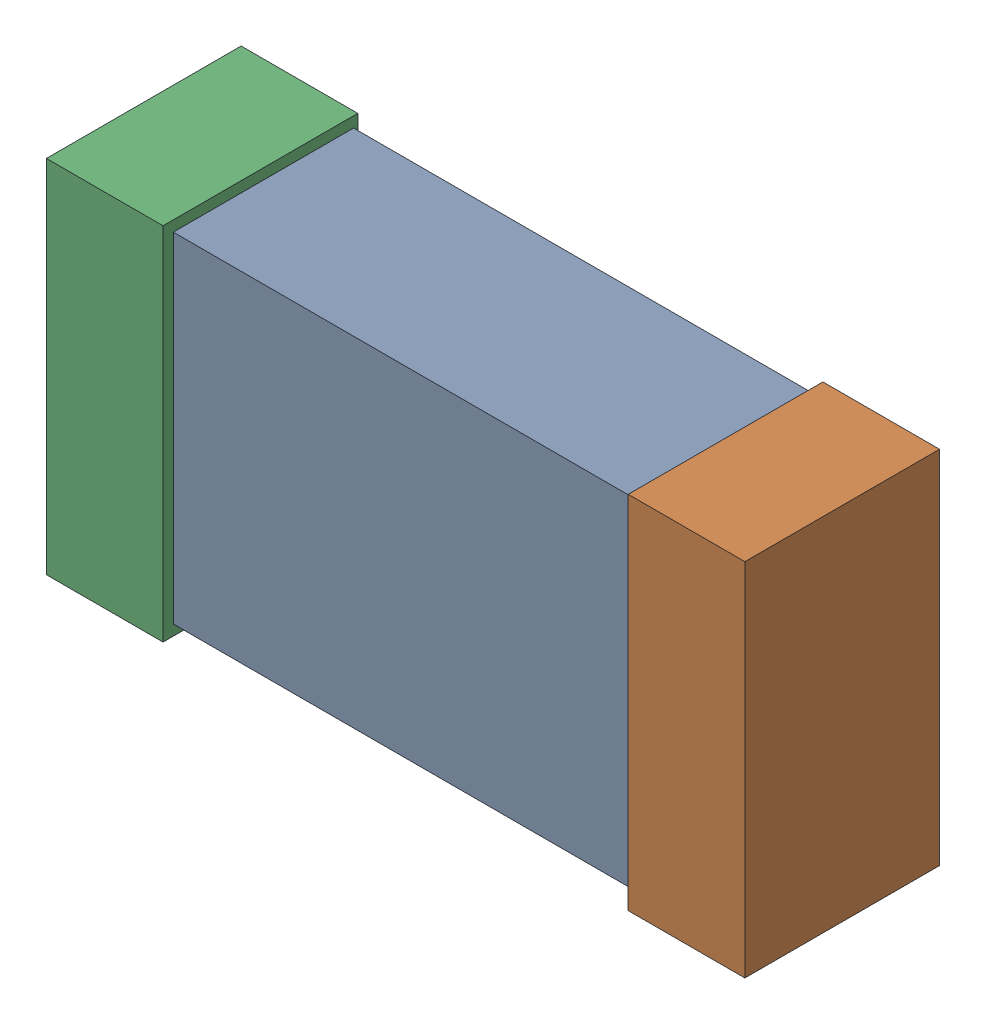
SolidWorks assembly R2, configuration Default. Lengths in mm.
Overall size (1.65 0.85 0.46).
6 component instances, 2 part files, 0 mates.
Components (placement in the parent):
- 432120720_14-1: 432120720_14 [Default] at (48.1003 12.0634 -0.8615) size (1.5 0.8 0.42)
  - Extruded (12)-1: Extruded (12) [Default] at origin size (1.5 0.8 0.42)
- 432120464_30-1: 432120464_30 [Default] at (48.7861 12.0634 -0.8715) size (0.28 0.85 0.46)
  - Extruded (11)-1: Extruded (11) [Default] at origin size (0.28 0.85 0.46)
- 432120464_31-1: 432120464_31 [Default] at (47.4146 12.0634 -0.8715) size (0.28 0.85 0.46)
  - Extruded (11)-1: Extruded (11) [Default] at origin size (0.28 0.85 0.46)
